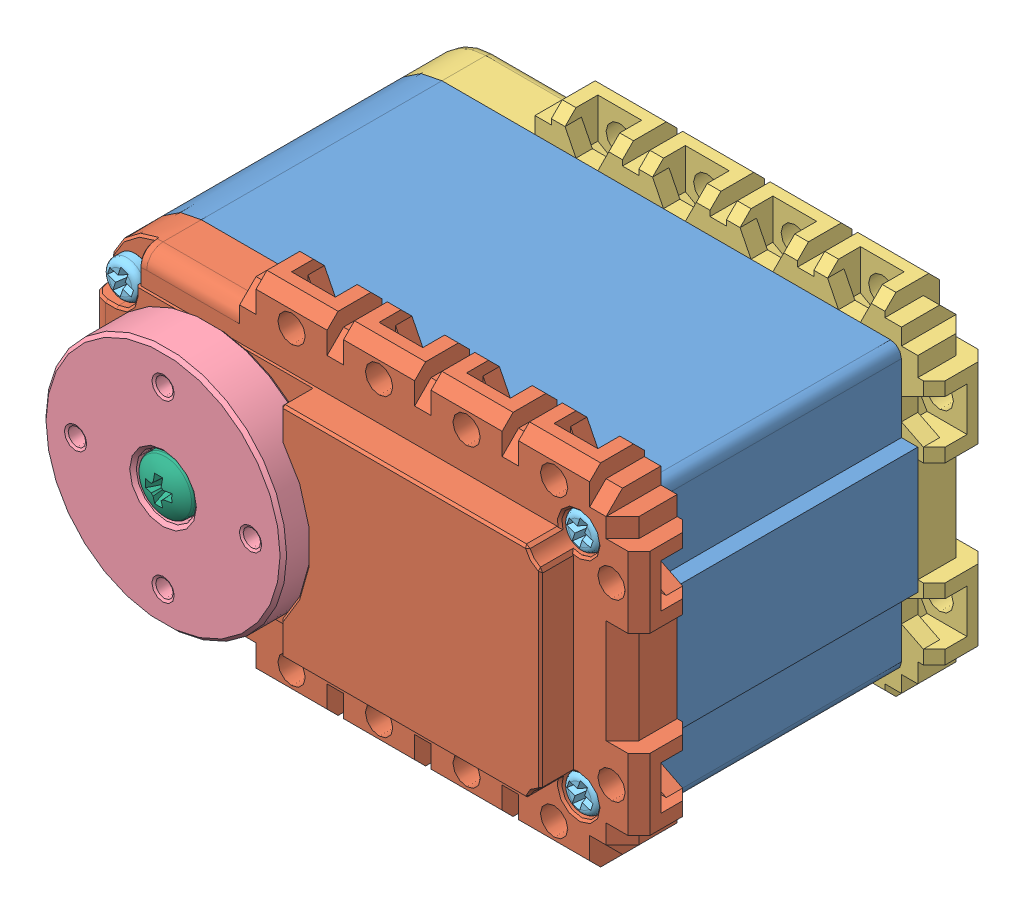
SolidWorks assembly AX-12A, configuration Default. Lengths in mm.
Overall size (50 32 40.55).
9 component instances, 6 part files, 19 mates.
Components (placement in the parent):
- AX-12A-01-1: AX-12A-01 [Default] at origin size (48.5 26 22)
- AX-12A-02-1: AX-12A-02 [Default] at (0 0 13.5) size (50 32 8)
- AX-12A-03-1: AX-12A-03 [Default] at (0 0 -13.5) x (1 0 0) z (0 0 -1) size (50 32 8)
- AX-12A-04-1: AX-12A-04 [Default] at (0 0 21) size (22 22 6.7)
- SetScrew-5: SetScrew [Default] at (33 10.4 14.5) x (0.31498 0.949098 0) z (0 0 -1) size (3.3 3.3 29.44)
- SetScrew-6: SetScrew [Default] at (-9 9.25 14.5) x (0.31498 0.949098 0) z (0 0 -1) size (3.3 3.3 29.44)
- SetScrew-7: SetScrew [Default] at (-9 -9.25 14.5) x (-0.958559 0.284893 0) z (0 0 -1) size (3.3 3.3 29.44)
- SetScrew-8: SetScrew [Default] at (33 -10.4 14.5) x (0.31498 0.949098 0) z (0 0 -1) size (3.3 3.3 29.44)
- pan head cross recess screw_iso1-1: pan head cross recess screw_iso1 [ISO 7045 - M2.5 x 8 - Z --- 8C] at (0 0 21.6) x (0 0 -1) z (1 0 0) size (10.05 5 5)
Mates (geometry in assembly coordinates):
- Coincident1: coincident anti-aligned: plane of AX-12A-01-1 through (0 0 11) normal (0 0 1); plane of AX-12A-02-1 through (0 0 11) normal (0 0 -1)
- Coincident2: coincident aligned: plane of AX-12A-01-1 through (0 0 0) normal (1 0 0); plane of AX-12A-02-1 through (0 0 13.5) normal (1 0 0)
- Coincident3: coincident aligned: plane of AX-12A-01-1 through (0 0 0) normal (0 1 0); plane of AX-12A-02-1 through (0 0 13.5) normal (0 1 0)
- Coincident4: coincident anti-aligned: plane of AX-12A-01-1 through (0 0 -11) normal (0 0 -1); plane of AX-12A-03-1 through (0 0 -11) normal (0 0 1)
- Coincident5: coincident aligned: plane of AX-12A-01-1 through (0 0 0) normal (1 0 0); plane of AX-12A-03-1 through (0 0 -13.5) normal (1 0 0)
- Coincident6: coincident anti-aligned: plane of AX-12A-01-1 through (0 0 0) normal (0 1 0); plane of AX-12A-03-1 through (0 0 -13.5) normal (0 -1 0)
- Concentric1: concentric anti-aligned: cylinder of AX-12A-02-1 through (0 0 13.75) axis (0 0 1) radius 4.75; cylinder of AX-12A-04-1 through (0 0 21) axis (0 0 -1) radius 4.5
- Distance1: distance = 5 mm aligned: plane of AX-12A-02-1 through (0 0 16) normal (0 0 1); plane of AX-12A-04-1 through (0 2.75 21) normal (0 0 1)
- Coincident7: coincident aligned: plane of AX-12A-04-1 through (0 0 21) normal (1 0 0)
- Concentric2: concentric aligned: cylinder of AX-12A-02-1 through (33 10.4 11) axis (0 0 1) radius 1; cylinder of SetScrew-5 through (33 10.4 14.5) axis (0 0 1) radius 0.85
- Coincident8: coincident anti-aligned: plane of AX-12A-02-1 through (0 0 14.5) normal (0 0 1); plane of SetScrew-5 through (33.8067 10.1323 14.5) normal (0 0 -1)
- Concentric3: concentric aligned: cylinder of AX-12A-02-1 through (-9 9.25 11) axis (0 0 1) radius 1; cylinder of SetScrew-6 through (-9 9.25 14.5) axis (0 0 1) radius 0.85
- Coincident9: coincident anti-aligned: plane of AX-12A-02-1 through (0 0 14.5) normal (0 0 1); plane of SetScrew-6 through (-8.1933 8.9823 14.5) normal (0 0 -1)
- Concentric4: concentric aligned: cylinder of AX-12A-02-1 through (-9 -9.25 11) axis (0 0 1) radius 1; cylinder of SetScrew-7 through (-9 -9.25 14.5) axis (0 0 1) radius 0.85
- Coincident10: coincident anti-aligned: plane of AX-12A-02-1 through (0 0 14.5) normal (0 0 1); plane of SetScrew-7 through (-8.7578 -8.4352 14.5) normal (0 0 -1)
- Concentric5: concentric aligned: cylinder of AX-12A-02-1 through (33 -10.4 11) axis (0 0 1) radius 1; cylinder of SetScrew-8 through (33 -10.4 14.5) axis (0 0 1) radius 0.85
- Coincident11: coincident anti-aligned: plane of AX-12A-02-1 through (0 0 14.5) normal (0 0 1); plane of SetScrew-8 through (33.8067 -10.6677 14.5) normal (0 0 -1)
- Concentric71: concentric anti-aligned: cylinder of AX-12A-04-1 through (0 0 21) axis (0 0 -1) radius 2.75; cylinder of pan head cross recess screw_iso-1 through (0 0 47) axis (0 0 1) radius 2.5
- Coincident131: coincident anti-aligned: plane of AX-12A-04-1 through (0 2.75 19.5) normal (0 0 1); plane of pan head cross recess screw_iso-1 through (0 1.25 19.5) normal (0 0 -1)
